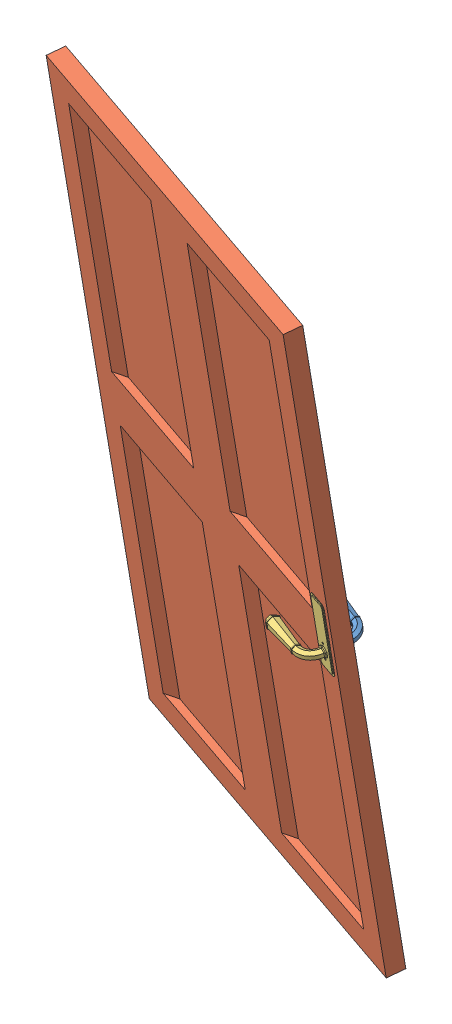
SolidWorks assembly Door assembly, configuration Default. Lengths in mm.
Overall size (1333.42 2472.06 870.76).
3 component instances, 3 part files, 6 mates.
Components (placement in the parent):
- door handle 1-1: door handle 1 [Default] at (934.7683 -832.1239 7007.9411) x (0.28471 0.174662 -0.942568) z (0.958161 -0.082077 0.274211) size (85.3 269.25 234.5)
- Door-1: Door [Default] at (461.6157 -555.9908 6912.5833) x (-0.958161 0.082077 -0.274211) z (-0.28471 -0.174662 0.942568) size (1300 2400 60)
- door handle 2-1: door handle 2 [Default] at (919.6218 -841.416 7058.0857) x (-0.28471 -0.174662 0.942568) z (0.958161 -0.082077 0.274211) size (85.3 270 234.5)
Mates (geometry in assembly coordinates):
- Coincident5: coincident aligned: line of Door-1 through (891.0622 -912.749 7036.2407) axis (0.958161 -0.082077 0.274211); line of i-1 through (891.0622 -912.749 7036.2407) axis (0.958161 -0.082077 0.274211)
- Coincident6: coincident anti-aligned: plane of Door-1 through (445.5011 -565.8767 6965.9326) normal (-0.28471 -0.174662 0.942568); plane of i-1 through (919.6218 -841.416 7058.0857) normal (0.28471 0.174662 -0.942568)
- Coincident7: coincident: line of Door-1 through (880.8072 -902.71 7038.6105) axis (0.656684 -0.751851 0.059035); plane of i-1 through (880.6364 -902.8148 7039.1761) normal (-0.69836 -0.635777 -0.328757)
- Coincident15: coincident: point of door handle 1-1; unknown of Door-1
- Coincident17: coincident anti-aligned: plane of door handle 1-1 through (934.7683 -832.1239 7007.9411) normal (-0.28471 -0.174662 0.942568); plane of Door-1 through (460.6477 -556.5846 6915.7881) normal (0.28471 0.174662 -0.942568)
- Coincident18: coincident: plane of door handle 1-1 through (960.0464 -907.2725 6997.4074) normal (0.656684 -0.751851 0.059035); line of Door-1 through (969.7519 -898.3861 7002.6223) axis (-0.69836 -0.635777 -0.328757)
